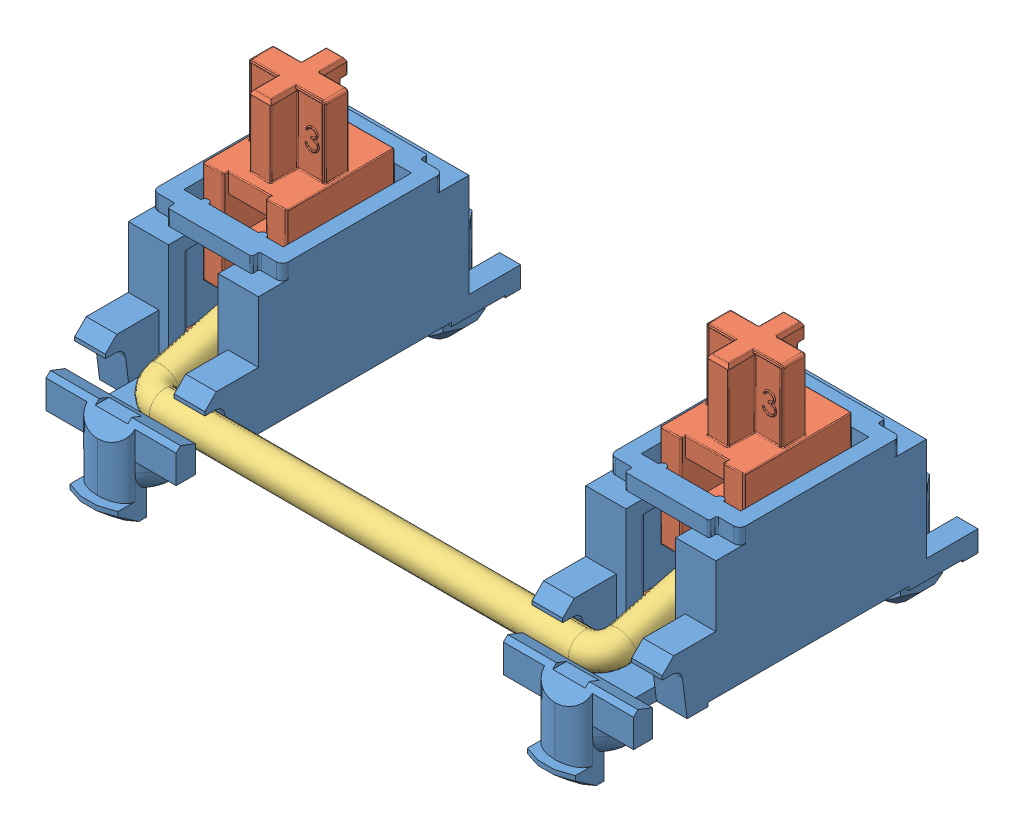
SolidWorks assembly Cherry MX Stabilizer, configuration Default. Lengths in mm.
Overall size (30.7 14.96 19.2).
5 component instances, 3 part files, 8 mates.
Components (placement in the parent):
- mx Stabilizer base 16828-1: mx Stabilizer base 16828 [Default] at origin size (6.8 10.1 19.2)
- mx Stabilizer key 16828-1: mx Stabilizer key 16828 [Default] at (0 4.757 0) size (4.41 11.95 8.3)
- metal stick 16828-1: metal stick 16828 [Default] at (11.95 0.6706 -3.0582) x (1 0 0) z (0 -0.243034 0.970018) size (25.5 1.6 12.2)
- mx Stabilizer base 16828-2: mx Stabilizer base 16828 [Default] at (23.9 0 0) size (6.8 10.1 19.2)
- mx Stabilizer key 16828-2: mx Stabilizer key 16828 [Default] at (23.9 4.757 0) size (4.41 11.95 8.3)
Mates (geometry in assembly coordinates):
- Coincident1: coincident aligned: plane of mx Stabilizer key 16828-1 through (0 4.757 0) normal (1 0 0)
- Coincident2: coincident aligned: plane of mx Stabilizer key 16828-1 through (0 4.757 0) normal (0 0 1)
- Coincident3: coincident aligned: plane of metal stick 16828-1 through (0 0.6706 -3.0582) normal (1 0 0)
- Tangent1: tangent anti-aligned: plane of mx Stabilizer base 16828-1 through (0 -2.9 10.5) normal (0 1 0); cylinder of metal stick 16828-1 through (22.9 -2.1 8) axis (-1 0 0) radius 0.8
- Tangent2: tangent anti-aligned: plane of mx Stabilizer base 16828-1 through (3.4 -3.6 8.8) normal (0 0 -1); cylinder of metal stick 16828-1 through (22.9 -2.1 8) axis (-1 0 0) radius 0.8
- Tangent3: tangent: line of mx Stabilizer key 16828-1 through (-1.1 0.757 -0.1115) axis (1 0 0); cylinder of metal stick 16828-1 through (0 -1.857 7.03) axis (0 0.243034 -0.970018) radius 0.8
- LimitDistance1: limit distance = 3.343 mm anti-aligned: plane of mx Stabilizer base 16828-1 through (3.4 2.1 5.5) normal (0 -1 0); plane of mx Stabilizer key 16828-1 through (0 -1.243 0) normal (0 1 0)
- LimitDistance2: limit distance = 0.107 mm aligned: plane of mx Stabilizer key 16828-1 through (0.45 -3.493 -3.8) normal (0 -1 0); plane of mx Stabilizer base 16828-1 through (3.4 -3.6 -4.6) normal (0 -1 0)
